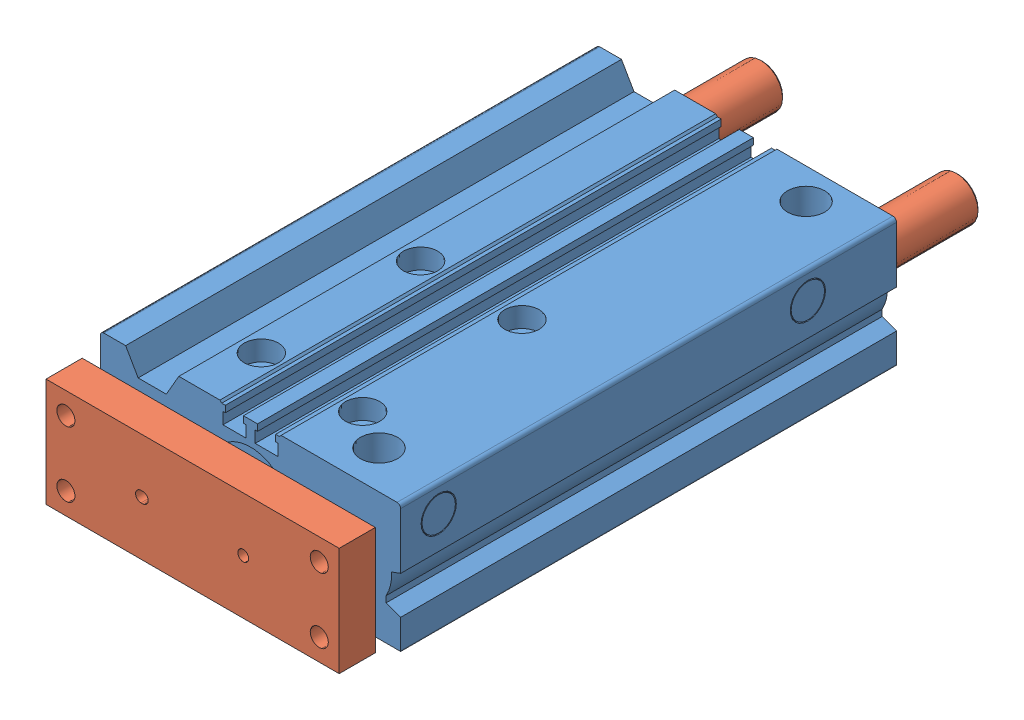
SolidWorks assembly AIR CYLINDER ASSEMBLY, configuration MGPM20N-100. Lengths in mm.
Overall size (83 36 184.5).
2 component instances, 2 part files, 3 mates.
Components (placement in the parent):
- 5321-31 SMC MGPM20N-100_MGPTube-1: 5321-31 SMC MGPM20N-100_MGPTube [20M] at origin size (83 36 137)
- 5321-31 SMC MGPM20N-100_MGPRod-1: 5321-31 SMC MGPM20N-100_MGPRod [20M] at (0 0 -52.5) size (81 30 184.5)
Mates (geometry in assembly coordinates):
- Concentric1: concentric: cylinder of 5321-31 SMC MGPM20N-100_MGPTube-1 through (0 0 -14.2836) axis (0 0 1) radius 5.05; cylinder of 5321-31 SMC MGPM20N-100_MGPRod-1 through (0 0 88.6421) axis (0 0 -1) radius 5
- Parallel1: parallel: plane of 5321-31 SMC MGPM20N-100_MGPRod-1 through (0 0 -52.5) normal (0 1 0); plane of assembly through (0 0 0) normal (0 1 0)
- LimitDistance1: limit distance = 6 mm: plane of 5321-31 SMC MGPM20N-100_MGPTube-1 through (0 0 68.5) normal (0 0 1); plane of 5321-31 SMC MGPM20N-100_MGPRod-1 through (-40.5 -15 74.5) normal (0 0 -1)
